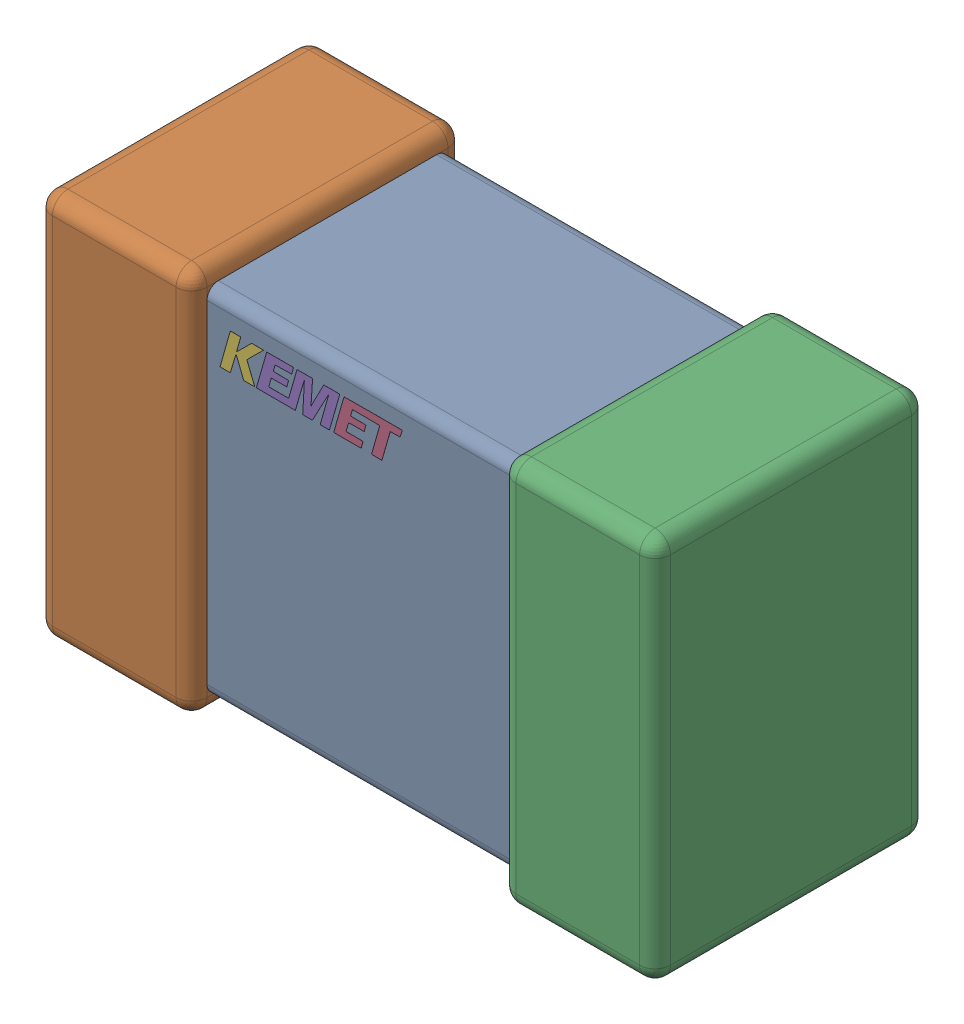
SolidWorks assembly C16.step, configuration Default. Lengths in mm.
Overall size (2 1.25 0.88).
3 component instances, 3 part files, 0 mates.
Components (placement in the parent):
- Cap_KEMET_C0805C472J3HAC_eec.step-1: Cap_KEMET_C0805C472J3HAC_eec.step [Default] at (24.523 58.828 0) size (1 1.15 0.78)
- Cap_KEMET_C0805C472J3HAC_eec-7.step-1: Cap_KEMET_C0805C472J3HAC_eec-7.step [Default] at (24.523 58.828 0) size (2 1.25 0.88)
- Cap_KEMET_C0805C472J3HAC_eec-8.step-1: Cap_KEMET_C0805C472J3HAC_eec-8.step [Default] at (24.523 58.828 0) size (0.59 0.12 0)
